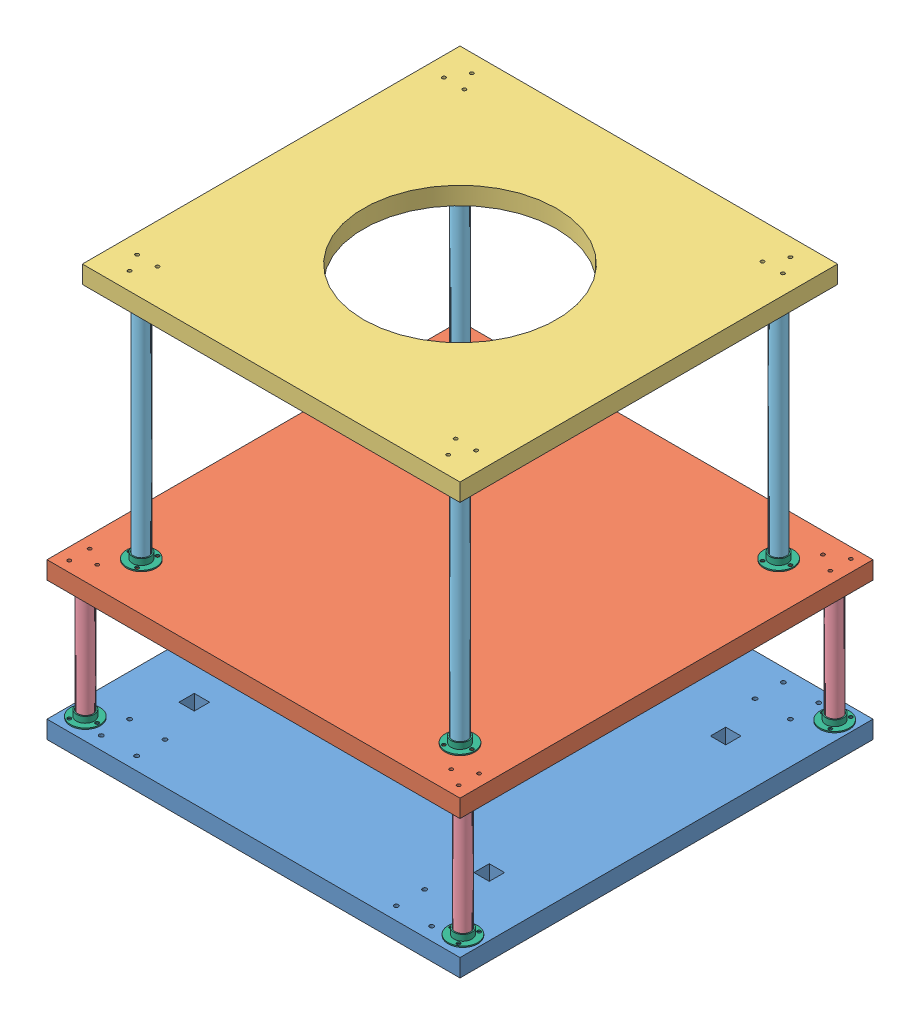
SolidWorks assembly Assem1, configuration Default. Lengths in mm.
Overall size (354.15 349 350).
27 component instances, 6 part files, 71 mates.
Components (placement in the parent):
- base_plate-1: base_plate [Default] at (-80.9251 158.2572 170.8802) x (0 1 0) z (0 0 1) size (15 350 350)
- floor_1_plate-1: floor_1_plate [Default] at (-36.2493 275.2572 334.3993) x (0 0 -1) z (1 0 0) size (350 15 350)
- floor_2_plate-1: floor_2_plate [Default] at (-100.3005 492.2572 233.5481) size (320 15 320)
- support_rod_floor_1-1: support_rod_floor_1 [Default] at (-127.7506 174.2572 489.5534) size (12.6 100 12.6)
- support_rod_floor_2-1: support_rod_floor_2 [Default] at (167.2494 291.2572 467.0534) size (12.6 200 12.6)
- support_rod_mount-1: support_rod_mount [Default] at (-127.7506 173.2572 489.5534) x (0.866025 0 -0.5) z (0.5 0 0.866025) size (25 6 25)
- support_rod_floor_1-2: support_rod_floor_1 [Default] at (192.2494 174.2572 489.5534) size (12.6 100 12.6)
- support_rod_mount-2: support_rod_mount [Default] at (192.2494 173.2572 489.5534) x (0 0 -1) z (1 0 0) size (25 6 25)
- support_rod_floor_1-3: support_rod_floor_1 [Default] at (192.2494 174.2572 174.5534) size (12.6 100 12.6)
- support_rod_mount-3: support_rod_mount [Default] at (192.2494 173.2572 174.5534) x (0.866025 0 0.5) z (-0.5 0 0.866025) size (25 6 25)
- support_rod_floor_1-4: support_rod_floor_1 [Default] at (-127.7506 173.2572 174.5534) x (0.345968 0 -0.938246) z (0.938246 0 0.345968) size (12.6 100 12.6)
- support_rod_mount-4: support_rod_mount [Default] at (-127.7506 173.2572 174.5534) x (0.866025 0 -0.5) z (0.5 0 0.866025) size (25 6 25)
- support_rod_mount-5: support_rod_mount [Default] at (-127.7506 275.2572 489.5534) x (0.866025 0 0.5) z (0.5 0 -0.866025) size (25 6 25)
- support_rod_mount-6: support_rod_mount [Default] at (-127.7506 275.2572 174.5534) x (0 0 -1) z (-1 0 0) size (25 6 25)
- support_rod_mount-7: support_rod_mount [Default] at (192.2494 275.2572 174.5534) x (0 0 1) z (1 0 0) size (25 6 25)
- support_rod_mount-8: support_rod_mount [Default] at (192.2494 275.2572 489.5534) x (0.866025 0 -0.5) z (-0.5 0 -0.866025) size (25 6 25)
- support_rod_mount-9: support_rod_mount [Default] at (-102.7506 290.2572 467.0534) x (0.866025 0 0.5) z (-0.5 0 0.866025) size (25 6 25)
- support_rod_mount-10: support_rod_mount [Default] at (-102.7506 290.2572 197.0534) x (-0.866025 0 0.5) z (-0.5 0 -0.866025) size (25 6 25)
- support_rod_mount-11: support_rod_mount [Default] at (167.2494 290.2572 197.0534) x (-0.866025 0 -0.5) z (0.5 0 -0.866025) size (25 6 25)
- support_rod_mount-12: support_rod_mount [Default] at (167.2494 290.2572 467.0534) x (0.866025 0 -0.5) z (0.5 0 0.866025) size (25 6 25)
- support_rod_floor_2-2: support_rod_floor_2 [Default] at (-102.7506 291.2572 467.0534) size (12.6 200 12.6)
- support_rod_floor_2-3: support_rod_floor_2 [Default] at (-102.7506 291.2572 197.0534) x (0.675533 0 -0.73733) z (0.73733 0 0.675533) size (12.6 200 12.6)
- support_rod_floor_2-4: support_rod_floor_2 [Default] at (167.2494 291.2572 197.0534) size (12.6 200 12.6)
- support_rod_mount-13: support_rod_mount [Default] at (-102.7506 492.2572 467.0534) x (-0.5 0 -0.866025) z (-0.866025 0 0.5) size (25 6 25)
- support_rod_mount-14: support_rod_mount [Default] at (167.2494 492.2572 467.0534) x (-0.5 0 -0.866025) z (-0.866025 0 0.5) size (25 6 25)
- support_rod_mount-15: support_rod_mount [Default] at (167.2494 492.2572 197.0534) x (-1 0 0) z (0 0 1) size (25 6 25)
- support_rod_mount-16: support_rod_mount [Default] at (-102.7506 492.2572 197.0534) x (0.5 0 -0.866025) z (-0.866025 0 -0.5) size (25 6 25)
Mates (geometry in assembly coordinates):
- Coincident1: coincident anti-aligned: plane of base_plate-1 through (-80.9251 173.2572 170.8802) normal (0 1 0); plane of support_rod_mount-1 through (-127.7506 173.2572 489.5534) normal (0 -1 0)
- Concentric1: concentric aligned: cylinder of base_plate-1 through (-117.7506 173.2572 489.5534) axis (0 -1 0) radius 1.5; cylinder of support_rod_mount-1 through (-117.7506 174.2572 489.5534) axis (0 -1 0) radius 1.5
- Concentric2: concentric aligned: cylinder of base_plate-1 through (-132.7506 173.2572 498.2137) axis (0 -1 0) radius 1.5; cylinder of support_rod_mount-1 through (-132.7506 174.2572 498.2137) axis (0 -1 0) radius 1.5
- Coincident2: coincident anti-aligned: plane of support_rod_floor_1-1 through (-127.7506 174.2572 489.5534) normal (0 -1 0); plane of support_rod_mount-1 through (-127.7506 174.2572 489.5534) normal (0 1 0)
- Concentric3: concentric aligned: cylinder of support_rod_floor_1-1 through (-127.7506 274.2572 489.5534) axis (0 -1 0) radius 6.3; cylinder of support_rod_mount-1 through (-127.7506 179.2572 489.5534) axis (0 -1 0) radius 6.5
- Coincident3: coincident anti-aligned: plane of base_plate-1 through (-80.9251 173.2572 170.8802) normal (0 1 0); plane of support_rod_mount-2 through (192.2494 173.2572 489.5534) normal (0 -1 0)
- Concentric4: concentric aligned: cylinder of base_plate-1 through (197.2494 173.2572 498.2137) axis (0 -1 0) radius 1.5; cylinder of support_rod_mount-2 through (197.2494 174.2572 498.2137) axis (0 -1 0) radius 1.5
- Concentric5: concentric aligned: cylinder of base_plate-1 through (182.2494 173.2572 489.5534) axis (0 -1 0) radius 1.5; cylinder of support_rod_mount-2 through (182.2494 174.2572 489.5534) axis (0 -1 0) radius 1.5
- Coincident4: coincident anti-aligned: plane of support_rod_floor_1-2 through (192.2494 174.2572 489.5534) normal (0 -1 0); plane of support_rod_mount-2 through (192.2494 174.2572 489.5534) normal (0 1 0)
- Concentric7: concentric aligned: cylinder of support_rod_floor_1-2 through (192.2494 274.2572 489.5534) axis (0 -1 0) radius 6.3; cylinder of support_rod_mount-2 through (192.2494 179.2572 489.5534) axis (0 -1 0) radius 6.5
- Coincident5: coincident anti-aligned: plane of base_plate-1 through (-80.9251 173.2572 170.8802) normal (0 1 0); plane of support_rod_mount-3 through (192.2494 173.2572 174.5534) normal (0 -1 0)
- Concentric8: concentric aligned: cylinder of base_plate-1 through (182.2494 173.2572 174.5534) axis (0 -1 0) radius 1.5; cylinder of support_rod_mount-3 through (182.2494 174.2572 174.5534) axis (0 -1 0) radius 1.5
- Concentric9: concentric aligned: cylinder of base_plate-1 through (197.2494 173.2572 183.2137) axis (0 -1 0) radius 1.5; cylinder of support_rod_mount-3 through (197.2494 174.2572 183.2137) axis (0 -1 0) radius 1.5
- Coincident6: coincident anti-aligned: plane of support_rod_floor_1-3 through (192.2494 174.2572 174.5534) normal (0 -1 0); plane of support_rod_mount-3 through (192.2494 174.2572 174.5534) normal (0 1 0)
- Concentric10: concentric aligned: cylinder of support_rod_floor_1-3 through (192.2494 274.2572 174.5534) axis (0 -1 0) radius 6.3; cylinder of support_rod_mount-3 through (192.2494 179.2572 174.5534) axis (0 -1 0) radius 6.5
- Coincident7: coincident anti-aligned: plane of base_plate-1 through (-80.9251 173.2572 170.8802) normal (0 1 0); plane of support_rod_mount-4 through (-127.7506 173.2572 174.5534) normal (0 -1 0)
- Concentric11: concentric aligned: cylinder of base_plate-1 through (-132.7506 173.2572 165.8932) axis (0 -1 0) radius 1.5; cylinder of support_rod_mount-4 through (-132.7506 174.2572 165.8932) axis (0 -1 0) radius 1.5
- Concentric12: concentric aligned: cylinder of base_plate-1 through (-117.7506 173.2572 174.5534) axis (0 -1 0) radius 1.5; cylinder of support_rod_mount-4 through (-117.7506 174.2572 174.5534) axis (0 -1 0) radius 1.5
- Coincident8: coincident anti-aligned: plane of base_plate-1 through (-80.9251 173.2572 170.8802) normal (0 1 0); plane of support_rod_floor_1-4 through (-127.7506 173.2572 174.5534) normal (0 -1 0)
- Concentric13: concentric aligned: cylinder of support_rod_floor_1-4 through (-127.7506 273.2572 174.5534) axis (0 -1 0) radius 6.3; cylinder of support_rod_mount-4 through (-127.7506 179.2572 174.5534) axis (0 -1 0) radius 6.5
- Coincident10: coincident anti-aligned: plane of floor_1_plate-1 through (-36.2493 275.2572 334.3993) normal (0 -1 0); plane of support_rod_mount-5 through (-127.7506 275.2572 489.5534) normal (0 1 0)
- Concentric14: concentric anti-aligned: cylinder of floor_1_plate-1 through (-132.7506 290.2572 498.2137) axis (0 -1 0) radius 1.5; cylinder of support_rod_mount-5 through (-132.7506 274.2572 498.2137) axis (0 1 0) radius 1.5
- Concentric15: concentric anti-aligned: cylinder of floor_1_plate-1 through (-132.7506 290.2572 480.8932) axis (0 -1 0) radius 1.5; cylinder of support_rod_mount-5 through (-132.7506 274.2572 480.8932) axis (0 1 0) radius 1.5
- Coincident11: coincident anti-aligned: plane of floor_1_plate-1 through (-36.2493 275.2572 334.3993) normal (0 -1 0); plane of support_rod_mount-6 through (-127.7506 275.2572 174.5534) normal (0 1 0)
- Concentric16: concentric anti-aligned: cylinder of floor_1_plate-1 through (-132.7506 290.2572 183.2137) axis (0 -1 0) radius 1.5; cylinder of support_rod_mount-6 through (-132.7506 274.2572 183.2137) axis (0 1 0) radius 1.5
- Concentric17: concentric anti-aligned: cylinder of floor_1_plate-1 through (-132.7506 290.2572 165.8932) axis (0 -1 0) radius 1.5; cylinder of support_rod_mount-6 through (-132.7506 274.2572 165.8932) axis (0 1 0) radius 1.5
- Coincident13: coincident anti-aligned: plane of floor_1_plate-1 through (-36.2493 275.2572 334.3993) normal (0 -1 0); plane of support_rod_mount-7 through (192.2494 275.2572 174.5534) normal (0 1 0)
- Concentric20: concentric anti-aligned: cylinder of floor_1_plate-1 through (182.2494 290.2572 174.5534) axis (0 -1 0) radius 1.5; cylinder of support_rod_mount-7 through (182.2494 274.2572 174.5534) axis (0 1 0) radius 1.5
- Concentric21: concentric anti-aligned: cylinder of floor_1_plate-1 through (197.2494 290.2572 165.8932) axis (0 -1 0) radius 1.5; cylinder of support_rod_mount-7 through (197.2494 274.2572 165.8932) axis (0 1 0) radius 1.5
- Coincident14: coincident anti-aligned: plane of floor_1_plate-1 through (-36.2493 275.2572 334.3993) normal (0 -1 0); plane of support_rod_mount-8 through (192.2494 275.2572 489.5534) normal (0 1 0)
- Concentric22: concentric anti-aligned: cylinder of floor_1_plate-1 through (197.2494 290.2572 498.2137) axis (0 -1 0) radius 1.5; cylinder of support_rod_mount-8 through (197.2494 274.2572 498.2137) axis (0 1 0) radius 1.5
- Concentric23: concentric anti-aligned: cylinder of floor_1_plate-1 through (182.2494 290.2572 489.5534) axis (0 -1 0) radius 1.5; cylinder of support_rod_mount-8 through (182.2494 274.2572 489.5534) axis (0 1 0) radius 1.5
- Coincident15: coincident anti-aligned: circle of support_rod_floor_1-1; plane of support_rod_mount-5 through (-127.7506 274.2572 489.5534) normal (0 -1 0)
- Coincident18: coincident anti-aligned: plane of support_rod_floor_1-1 through (-127.7506 274.2572 489.5534) normal (0 1 0); plane of support_rod_mount-5 through (-127.7506 274.2572 489.5534) normal (0 -1 0)
- Concentric25: concentric anti-aligned: cylinder of support_rod_floor_1-1 through (-127.7506 274.2572 489.5534) axis (0 -1 0) radius 6.3; cylinder of support_rod_mount-5 through (-127.7506 269.2572 489.5534) axis (0 1 0) radius 6.5
- Concentric26: concentric anti-aligned: cylinder of support_rod_floor_1-3 through (192.2494 274.2572 174.5534) axis (0 -1 0) radius 6.3; cylinder of support_rod_mount-7 through (192.2494 269.2572 174.5534) axis (0 1 0) radius 6.5
- Coincident19: coincident anti-aligned: plane of floor_1_plate-1 through (-36.2493 290.2572 334.3993) normal (0 1 0); plane of support_rod_mount-9 through (-102.7506 290.2572 467.0534) normal (0 -1 0)
- Concentric27: concentric aligned: cylinder of floor_1_plate-1 through (-112.7506 290.2572 467.0534) axis (0 -1 0) radius 1.5; cylinder of support_rod_mount-9 through (-112.7506 291.2572 467.0534) axis (0 -1 0) radius 1.5
- Concentric28: concentric aligned: cylinder of floor_1_plate-1 through (-97.7506 290.2572 458.3932) axis (0 -1 0) radius 1.5; cylinder of support_rod_mount-9 through (-97.7506 291.2572 458.3932) axis (0 -1 0) radius 1.5
- Coincident21: coincident anti-aligned: plane of floor_1_plate-1 through (-36.2493 290.2572 334.3993) normal (0 1 0); plane of support_rod_mount-10 through (-102.7506 290.2572 197.0534) normal (0 -1 0)
- Concentric29: concentric aligned: cylinder of floor_1_plate-1 through (-97.7506 290.2572 205.7137) axis (0 -1 0) radius 1.5; cylinder of support_rod_mount-10 through (-97.7506 291.2572 205.7137) axis (0 -1 0) radius 1.5
- Concentric30: concentric aligned: cylinder of floor_1_plate-1 through (-97.7506 290.2572 188.3932) axis (0 -1 0) radius 1.5; cylinder of support_rod_mount-10 through (-97.7506 291.2572 188.3932) axis (0 -1 0) radius 1.5
- Coincident22: coincident anti-aligned: plane of floor_1_plate-1 through (-36.2493 290.2572 334.3993) normal (0 1 0); plane of support_rod_mount-11 through (167.2494 290.2572 197.0534) normal (0 -1 0)
- Concentric31: concentric aligned: cylinder of floor_1_plate-1 through (162.2494 290.2572 205.7137) axis (0 -1 0) radius 1.5; cylinder of support_rod_mount-11 through (162.2494 291.2572 205.7137) axis (0 -1 0) radius 1.5
- Concentric32: concentric aligned: cylinder of support_rod_mount-11 through (177.2494 291.2572 197.0534) axis (0 -1 0) radius 1.5; cylinder of floor_1_plate-1 through (177.2494 290.2572 197.0534) axis (0 -1 0) radius 1.5
- Coincident23: coincident anti-aligned: plane of floor_1_plate-1 through (-36.2493 290.2572 334.3993) normal (0 1 0); plane of support_rod_mount-12 through (167.2494 290.2572 467.0534) normal (0 -1 0)
- Concentric33: concentric aligned: cylinder of floor_1_plate-1 through (162.2494 290.2572 475.7137) axis (0 -1 0) radius 1.5; cylinder of support_rod_mount-12 through (162.2494 291.2572 475.7137) axis (0 -1 0) radius 1.5
- Concentric34: concentric aligned: cylinder of floor_1_plate-1 through (162.2494 290.2572 458.3932) axis (0 -1 0) radius 1.5; cylinder of support_rod_mount-12 through (162.2494 291.2572 458.3932) axis (0 -1 0) radius 1.5
- Coincident24: coincident anti-aligned: plane of support_rod_floor_2-1 through (167.2494 291.2572 467.0534) normal (0 -1 0); plane of support_rod_mount-12 through (167.2494 291.2572 467.0534) normal (0 1 0)
- Concentric35: concentric aligned: cylinder of support_rod_floor_2-1 through (167.2494 491.2572 467.0534) axis (0 -1 0) radius 6.3; cylinder of support_rod_mount-12 through (167.2494 296.2572 467.0534) axis (0 -1 0) radius 6.5
- Coincident25: coincident anti-aligned: plane of support_rod_mount-9 through (-102.7506 291.2572 467.0534) normal (0 1 0); plane of support_rod_floor_2-2 through (-102.7506 291.2572 467.0534) normal (0 -1 0)
- Concentric36: concentric aligned: cylinder of support_rod_mount-9 through (-102.7506 296.2572 467.0534) axis (0 -1 0) radius 6.5; cylinder of support_rod_floor_2-2 through (-102.7506 491.2572 467.0534) axis (0 -1 0) radius 6.3
- Coincident26: coincident anti-aligned: plane of support_rod_mount-10 through (-102.7506 291.2572 197.0534) normal (0 1 0); plane of support_rod_floor_2-3 through (-102.7506 291.2572 197.0534) normal (0 -1 0)
- Concentric37: concentric aligned: cylinder of support_rod_mount-10 through (-102.7506 296.2572 197.0534) axis (0 -1 0) radius 6.5; cylinder of support_rod_floor_2-3 through (-102.7506 491.2572 197.0534) axis (0 -1 0) radius 6.3
- Coincident28: coincident anti-aligned: plane of support_rod_mount-11 through (167.2494 291.2572 197.0534) normal (0 1 0); plane of support_rod_floor_2-4 through (167.2494 291.2572 197.0534) normal (0 -1 0)
- Concentric38: concentric aligned: cylinder of support_rod_mount-11 through (167.2494 296.2572 197.0534) axis (0 -1 0) radius 6.5; cylinder of support_rod_floor_2-4 through (167.2494 491.2572 197.0534) axis (0 -1 0) radius 6.3
- Coincident30: coincident anti-aligned: plane of floor_2_plate-1 through (-100.3005 492.2572 233.5481) normal (0 -1 0); plane of support_rod_mount-13 through (-102.7506 492.2572 467.0534) normal (0 1 0)
- Concentric39: concentric anti-aligned: cylinder of floor_2_plate-1 through (-102.7506 507.2572 477.0534) axis (0 -1 0) radius 1.5; cylinder of support_rod_mount-13 through (-102.7506 491.2572 477.0534) axis (0 1 0) radius 1.5
- Concentric40: concentric anti-aligned: cylinder of floor_2_plate-1 through (-94.0904 507.2572 462.0534) axis (0 -1 0) radius 1.5; cylinder of support_rod_mount-13 through (-94.0904 491.2572 462.0534) axis (0 1 0) radius 1.5
- Coincident31: coincident anti-aligned: plane of floor_2_plate-1 through (-100.3005 492.2572 233.5481) normal (0 -1 0); plane of support_rod_mount-14 through (167.2494 492.2572 467.0534) normal (0 1 0)
- Concentric41: concentric anti-aligned: cylinder of floor_2_plate-1 through (167.2494 507.2572 477.0534) axis (0 -1 0) radius 1.5; cylinder of support_rod_mount-14 through (167.2494 491.2572 477.0534) axis (0 1 0) radius 1.5
- Concentric42: concentric anti-aligned: cylinder of floor_2_plate-1 through (175.9096 507.2572 462.0534) axis (0 -1 0) radius 1.5; cylinder of support_rod_mount-14 through (175.9096 491.2572 462.0534) axis (0 1 0) radius 1.5
- Coincident32: coincident anti-aligned: plane of floor_2_plate-1 through (-100.3005 492.2572 233.5481) normal (0 -1 0); plane of support_rod_mount-15 through (167.2494 492.2572 197.0534) normal (0 1 0)
- Concentric43: concentric anti-aligned: cylinder of floor_2_plate-1 through (175.9096 507.2572 202.0534) axis (0 -1 0) radius 1.5; cylinder of support_rod_mount-15 through (175.9096 491.2572 202.0534) axis (0 1 0) radius 1.5
- Concentric44: concentric anti-aligned: cylinder of floor_2_plate-1 through (158.5891 507.2572 202.0534) axis (0 -1 0) radius 1.5; cylinder of support_rod_mount-15 through (158.5891 491.2572 202.0534) axis (0 1 0) radius 1.5
- Coincident36: coincident anti-aligned: plane of floor_2_plate-1 through (-100.3005 492.2572 233.5481) normal (0 -1 0); plane of support_rod_mount-16 through (-102.7506 492.2572 197.0534) normal (0 1 0)
- Concentric47: concentric anti-aligned: cylinder of floor_2_plate-1 through (-111.4109 507.2572 202.0534) axis (0 -1 0) radius 1.5; cylinder of support_rod_mount-16 through (-111.4109 491.2572 202.0534) axis (0 1 0) radius 1.5
- Concentric48: concentric anti-aligned: cylinder of floor_2_plate-1 through (-94.0904 507.2572 202.0534) axis (0 -1 0) radius 1.5; cylinder of support_rod_mount-16 through (-94.0904 491.2572 202.0534) axis (0 1 0) radius 1.5
- Coincident37: coincident anti-aligned: plane of support_rod_floor_2-1 through (167.2494 491.2572 467.0534) normal (0 1 0); plane of support_rod_mount-14 through (167.2494 491.2572 467.0534) normal (0 -1 0)
- Concentric49: concentric anti-aligned: cylinder of support_rod_floor_2-1 through (167.2494 491.2572 467.0534) axis (0 -1 0) radius 6.3; cylinder of support_rod_mount-14 through (167.2494 486.2572 467.0534) axis (0 1 0) radius 6.5
- Concentric50: concentric anti-aligned: cylinder of support_rod_floor_2-3 through (-102.7506 491.2572 197.0534) axis (0 -1 0) radius 6.3; cylinder of support_rod_mount-16 through (-102.7506 486.2572 197.0534) axis (0 1 0) radius 6.5
